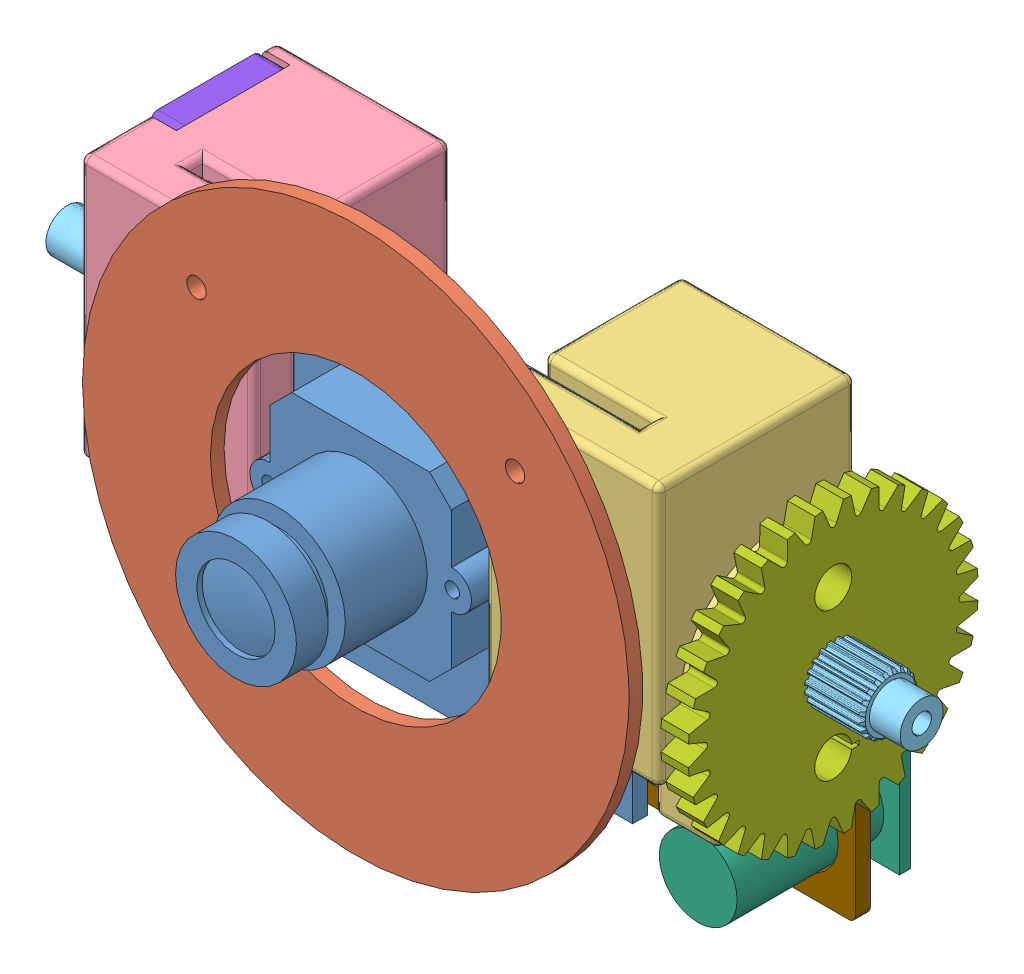
SolidWorks assembly cam w_lightring, configuration Default. Lengths in mm.
Overall size (99.26 65.76 47.57).
9 component instances, 9 part files, 25 mates.
Components (placement in the parent):
- RCM-Cam-1: RCM-Cam [Default] at origin size (51 38.31 29.45)
- light-ring-1: light-ring [Default] at (0 0 6.8326) size (63.5 63.5 1.59)
- cam bracket_L-1: cam bracket_L [Default] at (59.113 9.91 6.8326) x (0 0 -1) z (1 0 0) size (26.62 40 22.73)
- cam bracket_R-1: cam bracket_R [Default] at (-8.113 9.91 -16.0274) x (0 0 1) z (-1 0 0) size (22.86 40 20.19)
- 13x_Custom Axle w-ends-and-encoder-end IN-2: 13x_Custom Axle w-ends-and-encoder-end IN [Default] at (25.5 17.4411 -7.7016) x (0 -0.793114 0.609073) z (1 0 0) size (6.65 6.65 99.26)
- Thermal-1: Thermal [Default] at (58.7026 -12.95 -22.8219) x (0 1 0) z (0 0 1) size (21.34 19.05 20.73)
- 32T Gear_Custom Axle w-2mntholes-1: 32T Gear_Custom Axle w-2mntholes [Default] at (63.2532 17.4411 -7.7016) x (0 -1 0) z (1 0 0) size (33.64 33.64 3.2)
- camsideplate_driven-2: camsideplate_driven [Default] at (-6.462 17.4411 -7.7016) x (0 -1 0) z (1 0 0) size (40 12.7 3.2)
- thermalsensor_mount-1: thermalsensor_mount [Default] at (25.5 19.155 -16.0274) x (1 0 0) z (0 0 -1) size (67.23 24.77 1.71)
Mates (geometry in assembly coordinates):
- Concentric1: concentric: cylinder of RCM-Cam-1 through (44 35.31 -4.4901) axis (0 0 1) radius 1.5875; cylinder of light-ring-1 through (44 35.31 11.6171) axis (0 0 -1) radius 1.1303
- Concentric2: concentric: cylinder of RCM-Cam-1 through (7 35.31 -4.4901) axis (0 0 1) radius 1.5875; cylinder of light-ring-1 through (7 35.31 11.6171) axis (0 0 -1) radius 1.1303
- Concentric3: concentric: cylinder of RCM-Cam-1 through (25.5 19.155 17.3736) axis (0 0 -1) radius 7.747; cylinder of light-ring-1 through (25.5 19.155 8.4201) axis (0 0 -1) radius 16.891
- Distance2: distance = 5.08 mm: plane of light-ring-1 through (25.5 19.155 6.8326) normal (0 0 -1); plane of RCM-Cam-1 through (0 0 1.7526) normal (0 0 1)
- Coincident13: coincident: plane of RCM-Cam-1 through (0 0 1.7526) normal (0 0 1); plane of cam bracket_L-1 through (89.6448 40.39 1.7526) normal (0 0 -1)
- Concentric5: concentric: cylinder of RCM-Cam-1 through (44 35.31 -4.4901) axis (0 0 1) radius 1.5875; cylinder of cam bracket_L-1 through (44 35.31 -16.0274) axis (0 0 1) radius 1.5875
- Parallel6: parallel: plane of RCM-Cam-1 through (51 38.31 1.7526) normal (1 0 0); plane of cam bracket_L-1 through (59.113 40.39 -16.0274) normal (1 0 0)
- Coincident15: coincident: plane of RCM-Cam-1 through (0 0 1.7526) normal (0 0 1); plane of cam bracket_R-1 through (-38.6448 40.39 1.7526) normal (0 0 -1)
- Concentric6: concentric: cylinder of RCM-Cam-1 through (7 35.31 -4.4901) axis (0 0 1) radius 1.5875; cylinder of cam bracket_R-1 through (7 35.31 6.8326) axis (0 0 -1) radius 1.5875
- Parallel7: parallel: plane of RCM-Cam-1 through (0 38.31 1.7526) normal (-1 0 0); plane of cam bracket_R-1 through (-8.113 40.39 6.8326) normal (-1 0 0)
- Concentric8: concentric: cylinder of cam bracket_L-1 through (27.4253 17.4411 -7.7016) axis (1 0 0) radius 4.064; cylinder of 13x_Custom Axle w-ends-and-encoder-end IN-2 through (75.1291 17.4411 -7.7016) axis (-1 0 0) radius 2.5019
- Coincident17: coincident: line of RCM-Cam-1 through (25.5 38.31 1.7526) axis (0 -1 0); point of 13x_Custom Axle w-ends-and-encoder-end IN-2
- Parallel8: parallel: plane of light-ring-1 through (25.5 19.155 6.8326) normal (0 0 -1); plane of Thermal-1 through (58.7026 -12.95 -22.8219) normal (0 0 -1)
- Concentric15: concentric: cylinder of cam bracket_L-1 through (48.953 8.8686 -7.7016) axis (1 0 0) radius 1.7272; cylinder of 32T Gear_Custom Axle w-2mntholes-1 through (55.5464 8.8686 -7.7016) axis (1 0 0) radius 2.159
- Concentric16: concentric: cylinder of cam bracket_L-1 through (48.953 26.0136 -7.7016) axis (1 0 0) radius 1.7272; cylinder of 32T Gear_Custom Axle w-2mntholes-1 through (55.5464 26.0136 -7.7016) axis (1 0 0) radius 2.159
- Coincident20: coincident: plane of cam bracket_L-1 through (61.653 17.4411 -7.7016) normal (1 0 0); plane of 32T Gear_Custom Axle w-2mntholes-1 through (61.653 17.4411 -7.7016) normal (-1 0 0)
- Coincident21: coincident: plane of cam bracket_R-1 through (-4.8618 9.91 -16.0274) normal (-1 0 0); plane of camsideplate_driven-2 through (-4.8618 17.4411 -7.7016) normal (1 0 0)
- Concentric17: concentric: cylinder of cam bracket_R-1 through (4.587 8.8686 -7.7016) axis (-1 0 0) radius 1.7272; cylinder of camsideplate_driven-2 through (-4.8618 8.8686 -7.7016) axis (-1 0 0) radius 2.159
- Concentric18: concentric: cylinder of cam bracket_R-1 through (4.587 26.0136 -7.7016) axis (-1 0 0) radius 1.7272; cylinder of camsideplate_driven-2 through (-4.8618 26.0136 -7.7016) axis (-1 0 0) radius 2.159
- Parallel9: parallel: plane of cam bracket_L-1 through (59.113 0.385 6.8326) normal (0 -1 0); plane of Thermal-1 through (39.6526 1.02 -21.5519) normal (0 1 0)
- Coincident23: coincident: plane of cam bracket_R-1 through (-8.113 9.91 -16.0274) normal (0 0 -1); plane of thermalsensor_mount-1 through (25.5 19.155 -16.0274) normal (0 0 1)
- Concentric19: concentric: cylinder of cam bracket_L-1 through (54.3886 4.6395 -6.5024) axis (0 0 -1) radius 1.7272; cylinder of thermalsensor_mount-1 through (54.3886 4.6395 -17.7419) axis (0 0 1) radius 2.159
- Concentric20: concentric: cylinder of cam bracket_R-1 through (-0.1374 4.6395 -6.5024) axis (0 0 -1) radius 1.7272; cylinder of thermalsensor_mount-1 through (-0.1374 4.6395 -17.7419) axis (0 0 1) radius 2.159
- Concentric21: concentric: cylinder of Thermal-1 through (56.1626 -1.52 -21.5519) axis (0 0 -1) radius 1.5875; cylinder of thermalsensor_mount-1 through (56.1626 -1.52 -17.7419) axis (0 0 1) radius 1.1303
- Distance6: distance = 3.81 mm: plane of thermalsensor_mount-1 through (25.5 19.155 -17.7419) normal (0 0 -1); plane of Thermal-1 through (58.7026 -12.95 -21.5519) normal (0 0 1)
